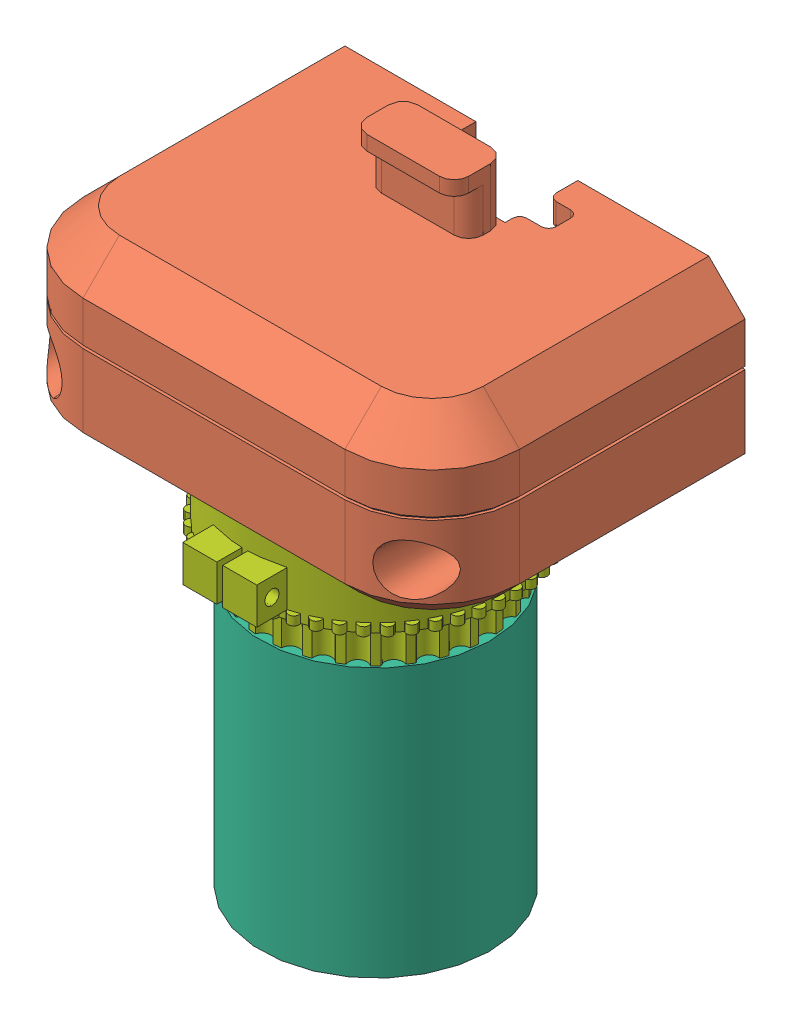
SolidWorks assembly camera_holder_assembly, configuration Default. Lengths in mm.
Overall size (102.25 185.08 88.2).
15 component instances, 7 part files, 18 mates.
Components (placement in the parent):
- rpi_hq_uvc_adapter_board-1: rpi_hq_uvc_adapter_board [Default] at (20.2172 82.4988 16.7828) x (-1 0 0) z (0 1 0)
- printed_base-1: printed_base [Printed Lid] at (20.2172 46.0688 -6.9672)
- m2.5_16mm_socket_cap_screw_91292A018-1: m2.5_16mm_socket_cap_screw_91292A018 [91292A018] at (5.2172 88.2388 1.7828) x (1 0 0) z (0 1 0)
- m2.5_16mm_socket_cap_screw_91292A018-2: m2.5_16mm_socket_cap_screw_91292A018 [91292A018] at (35.2172 88.2388 1.7828) x (1 0 0) z (0 1 0)
- m2.5_16mm_socket_cap_screw_91292A018-3: m2.5_16mm_socket_cap_screw_91292A018 [91292A018] at (35.2172 88.2388 31.7828) x (1 0 0) z (0 1 0)
- m2.5_16mm_socket_cap_screw_91292A018-4: m2.5_16mm_socket_cap_screw_91292A018 [91292A018] at (5.2172 88.2388 31.7828) x (1 0 0) z (0 1 0)
- printed_base_assembly-1: printed_base_assembly [Default] at (-1.6813 0 1.4527) size (102.25 179.33 88.2)
  - printed_base-1: printed_base [Printed Lower Base] at (21.8985 46.0688 -8.4198) size (102.25 179.33 88.2)
  - m3_heat_set_insert_94180A331-1: m3_heat_set_insert_94180A331 [94180A331] at (7.8985 78.5688 -5.4198) x (0.928039 0.372484 0) z (-0.372484 0.928039 0) size (5.56 4.12 5.56)
  - m3_heat_set_insert_94180A331-2: m3_heat_set_insert_94180A331 [94180A331] at (35.8985 78.5688 -5.4198) x (0.997541 -0.070079 0) z (0.070079 0.997541 0) size (5.56 4.12 5.56)
  - 5x9x2_oring-1: 5x9x2_oring [Default] at (3.6485 78.0688 10.3302) x (0.994492 0 -0.104809) z (0.104809 0 0.994492) size (9 3.15 9)
  - 5x9x2_oring-2: 5x9x2_oring [Default] at (40.1485 78.0688 10.3302) x (-0.984669 0 0.174435) z (-0.174435 0 -0.984669) size (9 3.15 9)
- sensor_with_lens-1: sensor_with_lens [Default] at origin size (41.64 98.45 42.27)
  - lens_mockup-1: lens_mockup [Default] at (20.2172 18.1388 16.7828) x (0.912257 0 0.409619) z (-0.409619 0 0.912257) size (31.5 38.9 31.5)
  - rasperry_pi_hq_camera-1: rasperry_pi_hq_camera [No Base Mount] at (1.2172 73.6388 35.7828) x (1 0 0) z (0 0 -1) size (38 98.45 41.45)
Mates (geometry in assembly coordinates):
- Width11: width aligned: plane of rpi_hq_uvc_adapter_board-1 through (39.2172 84.0688 35.7828) normal (0 0 1); plane of printed_base_assembly-1/printed_base-1 through (39.2172 84.0688 -2.2172) normal (0 0 -1); plane of rpi_hq_uvc_adapter_board-1 through (0.9672 25.0688 -2.4672) normal (0 0 1); plane of printed_base_assembly-1/printed_base-1 through (0.9672 25.0688 36.0328) normal (0 0 -1)
- Coincident722: coincident anti-aligned: plane of rpi_hq_uvc_adapter_board-1 through (20.2172 82.4988 16.7828) normal (0 -1 0); plane of printed_base_assembly-1/printed_base-1 through (20.2172 82.4988 -6.9672) normal (0 1 0)
- Width16: width aligned: plane of sensor_with_lens-1/rasperry_pi_hq_camera-1 through (39.2172 73.6388 0.2828) normal (1 0 0); plane of rpi_hq_uvc_adapter_board-1 through (1.2172 73.6388 33.2828) normal (-1 0 0); plane of sensor_with_lens-1/rasperry_pi_hq_camera-1 through (39.2172 84.0688 -2.2172) normal (1 0 0); plane of rpi_hq_uvc_adapter_board-1 through (1.2172 84.0688 -2.2172) normal (-1 0 0)
- Width17: width aligned: plane of sensor_with_lens-1/rasperry_pi_hq_camera-1 through (3.7172 73.6388 -2.2172) normal (0 0 -1); plane of rpi_hq_uvc_adapter_board-1 through (36.7172 73.6388 35.7828) normal (0 0 1); plane of sensor_with_lens-1/rasperry_pi_hq_camera-1 through (39.2172 84.0688 -2.2172) normal (0 0 -1); plane of rpi_hq_uvc_adapter_board-1 through (39.2172 84.0688 35.7828) normal (0 0 1)
- Width13: width aligned: plane of printed_base-1 through (50.2172 95.0688 27.0328) normal (1 0 0); plane of printed_base_assembly-1/printed_base-1 through (-9.7828 95.0688 -3.9672) normal (-1 0 0); plane of printed_base-1 through (50.2172 72.0688 39.0328) normal (1 0 0); plane of printed_base_assembly-1/printed_base-1 through (-9.7828 72.0688 39.0328) normal (-1 0 0)
- Coincident727: coincident aligned: plane of printed_base_assembly-1/printed_base-1 through (-9.7828 72.0688 39.0328) normal (0 0 1); plane of printed_base-1 through (2.2172 95.0688 39.0328) normal (0 0 1)
- Coincident728: coincident anti-aligned: plane of printed_base_assembly-1/printed_base-1 through (20.2172 84.0688 -6.9672) normal (0 1 0); plane of printed_base-1 through (2.2172 84.0688 27.0328) normal (0 -1 0)
- Concentric1090: concentric aligned: cylinder of sensor_with_lens-1/rasperry_pi_hq_camera-1 through (5.2172 72.2388 1.7828) axis (0 1 0) radius 2.5; cone of m2.5_16mm_socket_cap_screw_91292A018-1 through (5.2172 72.0138 1.7828) axis (0 1 0)
- Coincident734: coincident anti-aligned: plane of sensor_with_lens-1/rasperry_pi_hq_camera-1 through (20.2172 72.2388 16.7828) normal (0 -1 0); plane of m2.5_16mm_socket_cap_screw_91292A018-1 through (5.2172 72.2388 1.7828) normal (0 1 0)
- Concentric1089: concentric aligned: cylinder of sensor_with_lens-1/rasperry_pi_hq_camera-1 through (35.2172 72.2388 1.7828) axis (0 1 0) radius 2.5; cone of m2.5_16mm_socket_cap_screw_91292A018-2 through (35.2172 72.0138 1.7828) axis (0 1 0)
- Coincident733: coincident anti-aligned: plane of sensor_with_lens-1/rasperry_pi_hq_camera-1 through (20.2172 72.2388 16.7828) normal (0 -1 0); plane of m2.5_16mm_socket_cap_screw_91292A018-2 through (35.2172 72.2388 1.7828) normal (0 1 0)
- Concentric1088: concentric aligned: cylinder of sensor_with_lens-1/rasperry_pi_hq_camera-1 through (35.2172 72.2388 31.7828) axis (0 1 0) radius 2.5; cone of m2.5_16mm_socket_cap_screw_91292A018-3 through (35.2172 72.0138 31.7828) axis (0 1 0)
- Coincident732: coincident anti-aligned: plane of sensor_with_lens-1/rasperry_pi_hq_camera-1 through (20.2172 72.2388 16.7828) normal (0 -1 0); plane of m2.5_16mm_socket_cap_screw_91292A018-3 through (35.2172 72.2388 31.7828) normal (0 1 0)
- Concentric1087: concentric aligned: cylinder of sensor_with_lens-1/rasperry_pi_hq_camera-1 through (5.2172 72.2388 31.7828) axis (0 1 0) radius 2.5; cone of m2.5_16mm_socket_cap_screw_91292A018-4 through (5.2172 72.0138 31.7828) axis (0 1 0)
- Coincident731: coincident anti-aligned: plane of sensor_with_lens-1/rasperry_pi_hq_camera-1 through (20.2172 72.2388 16.7828) normal (0 -1 0); plane of m2.5_16mm_socket_cap_screw_91292A018-4 through (5.2172 72.2388 31.7828) normal (0 1 0)
- Width18: width anti-aligned: plane of sensor_with_lens-1/rasperry_pi_hq_camera-1 through (1.2172 73.6388 33.2828) normal (-1 0 0); plane of printed_base_assembly-1/printed_base-1 through (39.2172 73.6388 0.2828) normal (1 0 0); plane of sensor_with_lens-1/rasperry_pi_hq_camera-1 through (0.9672 25.0688 36.0328) normal (1 0 0); plane of printed_base_assembly-1/printed_base-1 through (39.4672 25.0688 36.0328) normal (-1 0 0)
- Width19: width anti-aligned: plane of sensor_with_lens-1/rasperry_pi_hq_camera-1 through (39.2172 73.6388 0.2828) normal (1 0 0); plane of printed_base_assembly-1/printed_base-1 through (1.2172 73.6388 33.2828) normal (-1 0 0); plane of sensor_with_lens-1/rasperry_pi_hq_camera-1 through (39.4672 25.0688 36.0328) normal (-1 0 0); plane of printed_base_assembly-1/printed_base-1 through (0.9672 25.0688 36.0328) normal (1 0 0)
- Coincident735: coincident anti-aligned: plane of sensor_with_lens-1/rasperry_pi_hq_camera-1 through (20.2172 73.6388 16.7828) normal (0 1 0); plane of printed_base_assembly-1/printed_base-1 through (20.2172 73.6388 -6.9672) normal (0 -1 0)
